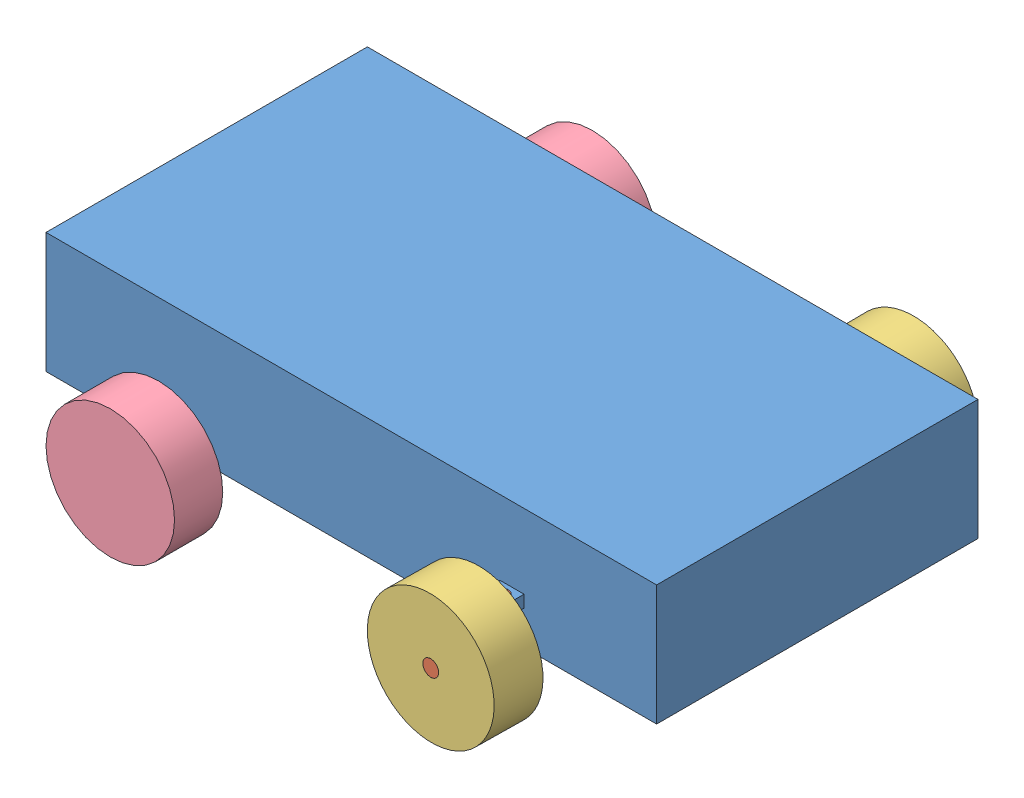
SolidWorks assembly Assembly, configuration Default. Lengths in mm.
Overall size (965.2 307.48 764.81).
6 component instances, 4 part files, 10 mates.
Components (placement in the parent):
- Body-1: Body [Default] at origin size (965.2 190.5 584.2)
- Front axle-3: Front axle [Default] at (254 73.025 273.05) x (0.999909 0 0.013511) z (-0.013511 0 0.999909) size (25.4 60.45 120.65)
- Wheel-7: Wheel [Default] at (253.571 25.273 304.7971) x (0.600365 0.799685 0.008112) z (-0.013511 0 0.999909) size (203.2 203.2 76.2)
- Rear Axle and Wheels-2: Rear Axle and Wheels [Default] at (-254 25.4 -381) x (-0.923313 0.384049 0) z (0 0 1) size (203.2 203.2 762)
- Front axle-5: Front axle [Default] at (254 73.025 -273.05) x (-0.999966 0 0.008284) z (-0.008284 0 -0.999966) size (25.4 60.45 120.65)
- Wheel-9: Wheel [Default] at (253.1057 25.273 -380.9963) x (-0.997661 0.067852 0.008265) z (0.008284 0 0.999966) size (203.2 203.2 76.2)
Mates (geometry in assembly coordinates):
- Coincident3: coincident aligned: plane of Body-1 through (234.95 73.025 292.1) normal (0 1 0); plane of Front axle-3 through (254 73.025 273.05) normal (0 1 0)
- Concentric2: concentric anti-aligned: cylinder of Body-1 through (254 -0.001 273.05) axis (0 1 0) radius 12.7; cylinder of Front axle-3 through (254 73.025 273.05) axis (0 -1 0) radius 12.7
- Concentric4: concentric anti-aligned: cylinder of Front axle-3 through (253.6568 25.273 298.4477) axis (-0.013511 0 0.999909) radius 12.7; cylinder of Wheel-7 through (252.5415 25.273 380.9901) axis (0.013511 0 -0.999909) radius 12.7
- Coincident5: coincident aligned: plane of Front axle-3 through (252.5415 25.273 380.9901) normal (-0.013511 0 0.999909); plane of Wheel-7 through (252.5415 25.273 380.9901) normal (-0.013511 0 0.999909)
- Concentric9: concentric anti-aligned: cylinder of Body-1 through (-254 25.4 -254.001) axis (0 0 1) radius 12.7; cylinder of Rear Axle and Wheels-2 through (-254 25.4 304.8) axis (0 0 -1) radius 12.7
- Concentric10: concentric anti-aligned: cylinder of Body-1 through (254 -0.001 -273.05) axis (0 1 0) radius 12.7; cylinder of Front axle-5 through (254 73.025 -273.05) axis (0 -1 0) radius 12.7
- Coincident6: coincident aligned: plane of Body-1 through (234.95 73.025 292.1) normal (0 1 0); plane of Front axle-5 through (254 73.025 -273.05) normal (0 1 0)
- Concentric12: concentric aligned: cylinder of Front axle-5 through (253.7896 25.273 -298.4491) axis (-0.008284 0 -0.999966) radius 12.7; cylinder of Wheel-9 through (253.737 25.273 -304.7989) axis (-0.008284 0 -0.999966) radius 101.6
- Coincident8: coincident aligned: plane of Front axle-5 through (253.1057 25.273 -380.9963) normal (-0.008284 0 -0.999966); plane of Wheel-9 through (253.1057 25.273 -380.9963) normal (-0.008284 0 -0.999966)
- Coincident10: coincident aligned: plane of Rear Axle and Wheels-2 through (-254 25.4 0) normal (0 0 1)
